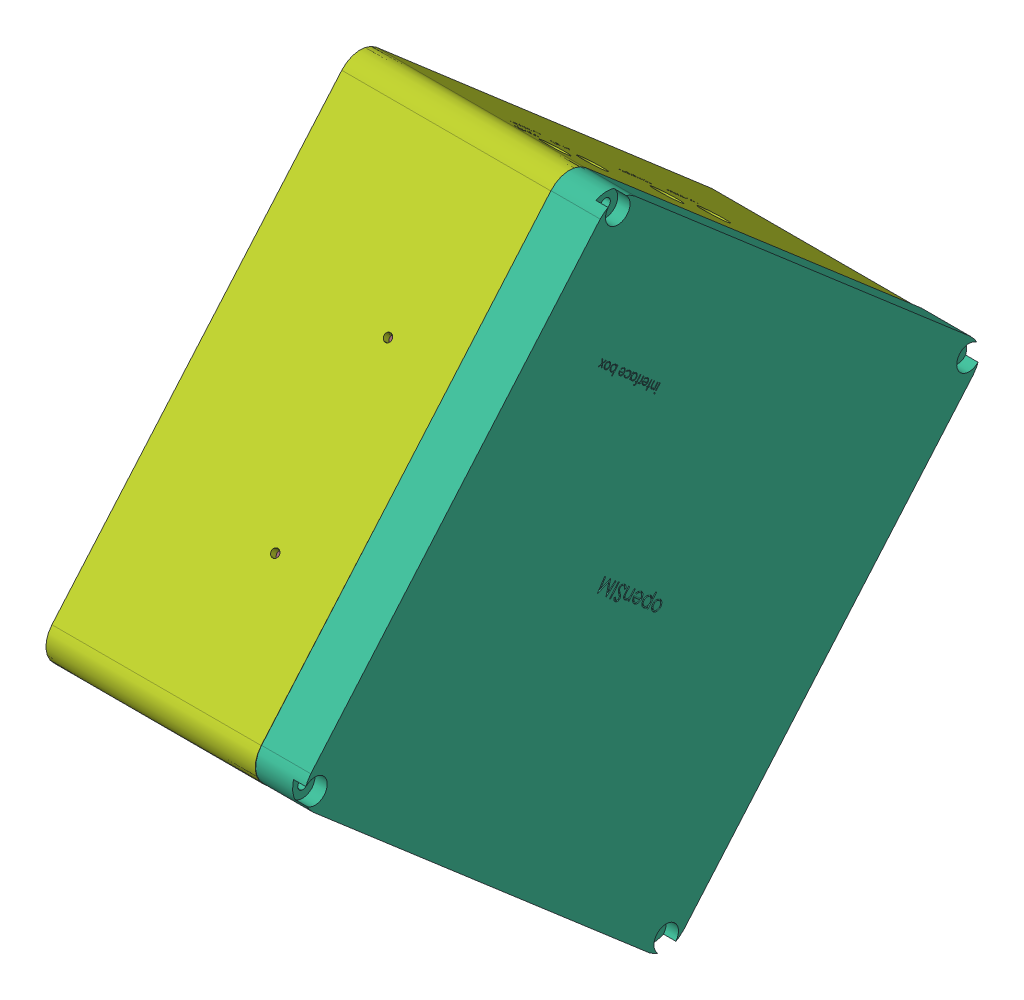
SolidWorks assembly Assem_openSIM_interfaceBox_2powerSupplies_openSIM_V2.0, configuration Default. Lengths in mm.
Overall size (105 282.28 282.23).
10 component instances, 9 part files, 25 mates.
Components (placement in the parent):
- clamp_DAQ_openSIM_V2.0-1: clamp_DAQ_openSIM_V2.0 [Default] at (17.1641 44.5347 131.6585) size (26 13 101)
- D SUB 15P male_openSIM_V2.0-1: D SUB 15P male_openSIM_V2.0 [Default] at (71.2141 35.1263 31.0923) x (0 0.756481 -0.654016) z (-1 0 0) size (39.1 17.44 12.5)
- delta_06ab2d_openSIM_V2.0-1: delta_06ab2d_openSIM_V2.0 [Default] at (20.1641 -56.2159 110.0623) x (1 0 0) z (0 0.654016 0.756481) size (64.5 49.63 57)
- interfaceBox_holder_powerSupply_openSIM_V2.0-1: interfaceBox_holder_powerSupply_openSIM_V2.0 [Default] at (62.1641 84.5025 125.5086) x (0 -0.654016 -0.756481) z (0 -0.756481 0.654016) size (116 11 115)
- NI_USB_6001_daq_openSIM_V2.0-1: NI_USB_6001_daq_openSIM_V2.0 [Default] at (17.1641 117.8232 77.5111) x (0 -0.756481 0.654016) z (1 0 0) size (93.2 86.2 23.6)
- openSIM_interface_box_cover_openSIM_V2.0-1: openSIM_interface_box_cover_openSIM_V2.0 [Default] at (106.1641 -70.5707 122.3183) x (0 0.652963 0.75739) z (0 -0.75739 0.652963) size (200 22 200)
- openSIM_interface_box_lowerPart-1: openSIM_interface_box_lowerPart [Default] at (13.1641 60.0221 273.9507) x (0 -0.654016 -0.756481) z (0 -0.756481 0.654016) size (200 85 200)
- powerSupply1_openSIM_V2.0-1: powerSupply1_openSIM_V2.0 [Default] at (66.1641 11.6682 164.5056) x (1 0 0) z (0 -0.756481 0.654016) size (41.2 98.3 144.6)
- clamp_DAQ_openSIM_V2.0-2: clamp_DAQ_openSIM_V2.0 [Default] at (17.1641 -0.4403 71.7558) x (1 0 0) z (0 -0.756481 0.654016) size (26 13 101)
- powerSupply2_openSIM_V2.0-1: powerSupply2_openSIM_V2.0 [Default] at (17.1641 71.0478 187.0766) x (0 -0.756481 0.654016) z (0 0.654016 0.756481) size (150 40 100)
Mates (geometry in assembly coordinates):
- Coincident1: coincident anti-aligned: plane of interfaceBox_holder_powerSupply-1 through (66.1641 84.5025 125.5086) normal (1 0 0); plane of rws150b_outline-1 through (66.1641 73.1456 235.6148) normal (-1 0 0)
- Concentric1: concentric aligned: circle of interfaceBox_holder_powerSupply-1; circle of openSIM_interface_box_lowerPart-1
- Concentric2: concentric aligned: circle of interfaceBox_holder_powerSupply-1; circle of openSIM_interface_box_lowerPart-1
- Coincident5: coincident anti-aligned: plane of interfaceBox_holder_powerSupply-1 through (66.1641 171.5322 173.5789) normal (0 0.654016 0.756481); plane of openSIM_interface_box_lowerPart-1 through (92.1641 60.3295 269.7192) normal (0 -0.654016 -0.756481)
- Coincident6: coincident anti-aligned: plane of NI_USB_6001_daq-1 through (17.1641 117.8232 77.5111) normal (-1 0 0); plane of openSIM_interface_box_lowerPart-1 through (17.1641 60.0221 273.9507) normal (1 0 0)
- Coincident7: coincident anti-aligned: plane of NI_USB_6001_daq-1 through (40.7641 61.4471 12.3025) normal (0 -0.654016 -0.756481); plane of openSIM_interface_box_lowerPart-1 through (92.1641 -66.5495 122.9619) normal (0 0.654016 0.756481)
- Coincident8: coincident anti-aligned: plane of D SUB 15P male - FL15P7-K120 (FCT)-1 through (65.9641 21.0936 43.2243) normal (0 0.654016 0.756481); plane of openSIM_interface_box_lowerPart-1 through (7.1641 -70.781 122.6545) normal (0 -0.654016 -0.756481)
- Concentric3: concentric anti-aligned: circle of D SUB 15P male - FL15P7-K120 (FCT)-1; circle of openSIM_interface_box_lowerPart-1
- Coincident9: coincident aligned: cylinder of D SUB 15P male - FL15P7-K120 (FCT)-1; cylinder of openSIM_interface_box_lowerPart-1 through (71.2141 178.5255 171.4999) axis (0 -0.654016 -0.756481) radius 1.45
- Distance1: distance = 5 mm: line of powerSupply1_openSIM_V2.0-1 through (68.1641 97.6801 90.144) axis (0 -0.756481 0.654016); line of interfaceBox_holder_powerSupply_openSIM_V2.0-1 through (66.1641 8.6711 161.0389) axis (0 0.756481 -0.654016)
- Coincident15: coincident anti-aligned: line of interfaceBox_holder_powerSupply-1 through (66.1641 84.5369 248.7907) axis (0 -0.654016 -0.756481); line of rws150b_outline-1 through (66.1641 15.2652 168.6662) axis (0 0.654016 0.756481)
- Concentric4: concentric aligned: circle of NI_USB_6001_daq-1; circle of openSIM_interface_box_lowerPart-1
- Coincident16: coincident anti-aligned: plane of clamp_DAQ-1 through (17.1641 44.5347 131.6585) normal (-1 0 0); plane of openSIM_interface_box_lowerPart-1 through (17.1641 60.0221 273.9507) normal (1 0 0)
- Concentric6: concentric aligned: circle of clamp_DAQ-1; circle of openSIM_interface_box_lowerPart-1
- Coincident18: coincident anti-aligned: plane of openSIM_interface_box_lowerPart-1 through (17.1641 60.0221 273.9507) normal (1 0 0); plane of clamp_DAQ-2 through (17.1641 -0.4403 71.7558) normal (-1 0 0)
- Coincident20: coincident anti-aligned: plane of delta_06ab2d-1 through (77.9141 -54.5754 108.644) normal (0 0.654016 0.756481); plane of openSIM_interface_box_lowerPart-1 through (7.1641 -70.781 122.6545) normal (0 -0.654016 -0.756481)
- Concentric8: concentric anti-aligned: circle of delta_06ab2d-1; circle of openSIM_interface_box_lowerPart-1
- Coincident21: coincident anti-aligned: plane of openSIM_interface_box_cover-1 through (92.1641 -70.5707 122.3183) normal (-1 0 0); plane of openSIM_interface_box_lowerPart-1 through (92.1641 60.0221 273.9507) normal (1 0 0)
- Concentric9: concentric anti-aligned: circle of openSIM_interface_box_cover-1; circle of openSIM_interface_box_lowerPart-1
- Coincident22: coincident anti-aligned: plane of openSIM_interface_box_lowerPart-1 through (17.1641 60.0221 273.9507) normal (1 0 0); plane of powerSupply2-1 through (17.1641 71.0478 187.0766) normal (-1 0 0)
- Parallel5: parallel anti-aligned: plane of openSIM_interface_box_lowerPart-1 through (92.1641 60.3295 269.7192) normal (0 0.756481 -0.654016); plane of powerSupply2-1 through (57.1641 3.0051 180.4785) normal (0 -0.756481 0.654016)
- Distance2: distance = 15 mm: line of openSIM_interface_box_lowerPart-1 through (17.1641 53.7894 262.1544) axis (0 -0.654016 -0.756481); line of powerSupply2_openSIM_V2.0-1 through (17.1641 3.0051 180.4785) axis (0 0.654016 0.756481)
- Distance4: distance = 5 mm anti-aligned: plane of powerSupply2_openSIM_V2.0-1 through (57.1641 181.8788 158.0243) normal (0 0.654016 0.756481); plane of openSIM_interface_box_lowerPart-1 through (92.1641 60.3295 269.7192) normal (0 -0.654016 -0.756481)
- Concentric10: concentric aligned: circle of openSIM_interface_box_lowerPart-1; circle of clamp_DAQ_openSIM_V2.0-2
- Concentric11: concentric aligned: circle of openSIM_interface_box_lowerPart-1; circle of clamp_DAQ_openSIM_V2.0-2
